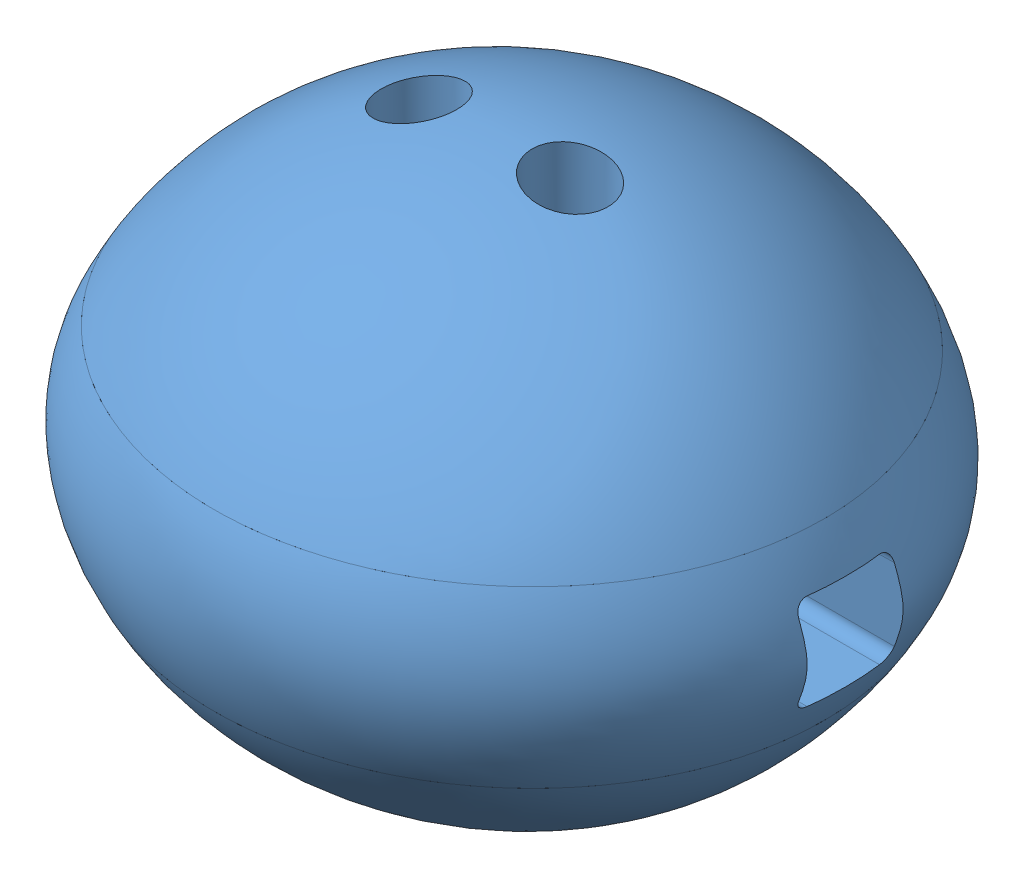
SolidWorks assembly Ballast_Weight_Assembly, configuration Default. Lengths in mm.
Overall size (152.07 114.4 139.83).
7 component instances, 3 part files, 14 mates.
Components (placement in the parent):
- Ballast_Weight-1: Ballast_Weight [Default] at origin size (152.07 114.4 139.83)
- Ballast_Weight-2: Ballast_Weight [Ballast Weight Outside] at origin size (144.63 51.5 137.25)
- Ballast_Weight-3: Ballast_Weight [Ballast Weight Outside] x (1 0 0) z (0 0 -1) size (144.63 51.5 137.25)
- 92196A554_18-8 STAINLESS STEEL SOCKET HEAD CAP SCREW-1: 92196A554_18-8 STAINLESS STEEL SOCKET HEAD CAP SCREW [92196A554] at (12.7 41.275 0) x (1 0 0) z (0 1 0) size (9.53 9.53 83.33)
- 92196A554_18-8 STAINLESS STEEL SOCKET HEAD CAP SCREW-2: 92196A554_18-8 STAINLESS STEEL SOCKET HEAD CAP SCREW [92196A554] at (-20.32 41.275 0) x (0.947644 0 -0.319328) z (0 1 0) size (9.53 9.53 83.33)
- 92673A113_ASTM F594 TYPE 18-8 STAINLESS STEEL HEX NUT-2: 92673A113_ASTM F594 TYPE 18-8 STAINLESS STEEL HEX NUT [92673A113] at (-20.32 37.7031 0) x (1 0 0) z (0 1 0) size (11.11 12.83 7.14)
- 92673A113_ASTM F594 TYPE 18-8 STAINLESS STEEL HEX NUT-3: 92673A113_ASTM F594 TYPE 18-8 STAINLESS STEEL HEX NUT [92673A113] at (12.7 37.7031 0) x (0.939231 0 0.343287) z (0 1 0) size (11.11 12.83 7.14)
Mates (geometry in assembly coordinates):
- Coincident3: coordinate: point of ?
- Coincident13: coincident anti-aligned: plane of Ballast_Weight-1 through (-76.2 19.05 -101.6) normal (0 1 0); plane of Ballast_Weight-2 through (-76.2018 19.05 -101.6) normal (0 -1 0)
- Coincident14: coincident aligned: plane of Ballast_Weight-2 through (0 0 0) normal (0 0 1); plane of assembly through (0 0 0) normal (0 0 1)
- Coincident15: coincident aligned: plane of Ballast_Weight-2 through (0 0 0) normal (1 0 0); plane of assembly through (0 0 0) normal (1 0 0)
- Coincident17: coincident anti-aligned: plane of Ballast_Weight-1 through (-76.2 -19.05 -101.6) normal (0 -1 0); plane of Ballast_Weight-3 through (-76.2018 -19.05 101.6) normal (0 1 0)
- Concentric1: concentric anti-aligned: cylinder of Ballast_Weight-1 through (-20.32 0 0) axis (0 -1 0) radius 3.3782; cylinder of Ballast_Weight-3 through (-20.32 0 0) axis (0 1 0) radius 3.2639
- Concentric3: concentric anti-aligned: cylinder of Ballast_Weight-1 through (12.7 0 0) axis (0 -1 0) radius 3.3782; cylinder of 92196A554_18-8 STAINLESS STEEL SOCKET HEAD CAP SCREW-1 through (12.7 -34.925 0) axis (0 1 0) radius 3.175
- Coincident18: coincident anti-aligned: plane of Ballast_Weight-3 through (12.7 -34.925 0) normal (0 -1 0); plane of 92196A554_18-8 STAINLESS STEEL SOCKET HEAD CAP SCREW-1 through (12.7 -34.925 0) normal (0 1 0)
- Concentric6: concentric anti-aligned: cylinder of Ballast_Weight-1 through (-20.32 0 0) axis (0 -1 0) radius 3.3782; cylinder of 92196A554_18-8 STAINLESS STEEL SOCKET HEAD CAP SCREW-2 through (-20.32 -34.925 0) axis (0 1 0) radius 3.175
- Coincident21: coincident anti-aligned: plane of Ballast_Weight-3 through (-20.32 -34.925 0) normal (0 -1 0); plane of 92196A554_18-8 STAINLESS STEEL SOCKET HEAD CAP SCREW-2 through (-20.32 -34.925 0) normal (0 1 0)
- Coincident22: coincident anti-aligned: cylinder of 92196A554_18-8 STAINLESS STEEL SOCKET HEAD CAP SCREW-1 through (12.7 -34.925 0) axis (0 1 0) radius 3.175; circle of 92673A113_ASTM F594 TYPE 18-8 STAINLESS STEEL HEX NUT-3
- Coincident23: coincident anti-aligned: circle of Ballast_Weight-2; plane of 92673A113_ASTM F594 TYPE 18-8 STAINLESS STEEL HEX NUT-3 through (8.5826 34.925 -4.9203) normal (0 -1 0)
- Coincident24: coincident anti-aligned: cylinder of 92196A554_18-8 STAINLESS STEEL SOCKET HEAD CAP SCREW-2 through (-20.32 -34.925 0) axis (0 1 0) radius 3.175; circle of 92673A113_ASTM F594 TYPE 18-8 STAINLESS STEEL HEX NUT-2
- Coincident25: coincident anti-aligned: circle of Ballast_Weight-2; plane of 92673A113_ASTM F594 TYPE 18-8 STAINLESS STEEL HEX NUT-2 through (-25.8762 34.925 -3.2079) normal (0 -1 0)
